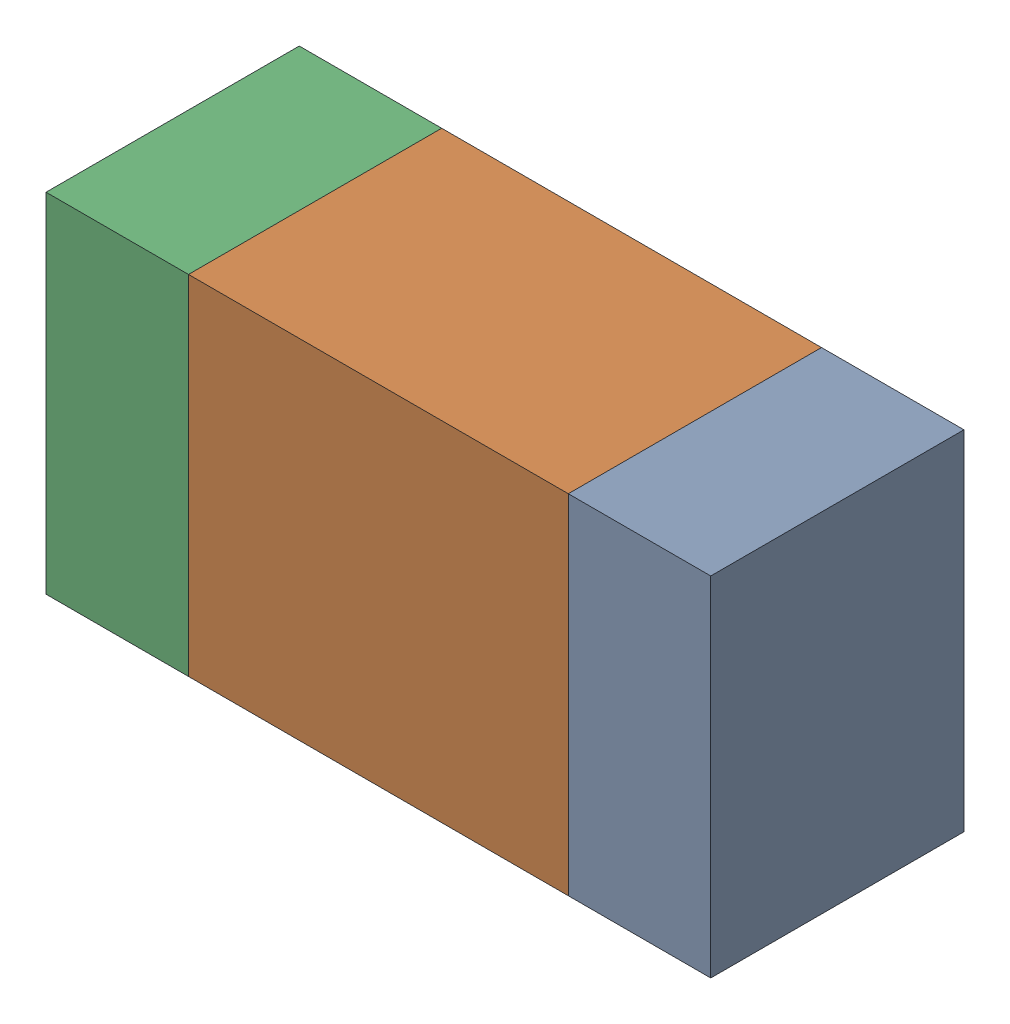
SolidWorks assembly R115_1PCB, configuration Default. Lengths in mm.
Overall size (1.05 0.55 0.4).
6 component instances, 2 part files, 0 mates.
Components (placement in the parent):
- 854785432-1: 854785432 [Default] at (112.8124 121.5999 0) size (0.22 0.55 0.4)
  - Extruded-1: Extruded [Default] at origin size (0.22 0.55 0.4)
- 854785568-1: 854785568 [Default] at (112.3999 121.5999 0) size (0.6 0.55 0.4)
  - Extruded_2-1: Extruded_2 [Default] at origin size (0.6 0.55 0.4)
- 854785432-2: 854785432 [Default] at (111.9874 121.5999 0) size (0.22 0.55 0.4)
  - Extruded-1: Extruded [Default] at origin size (0.22 0.55 0.4)
